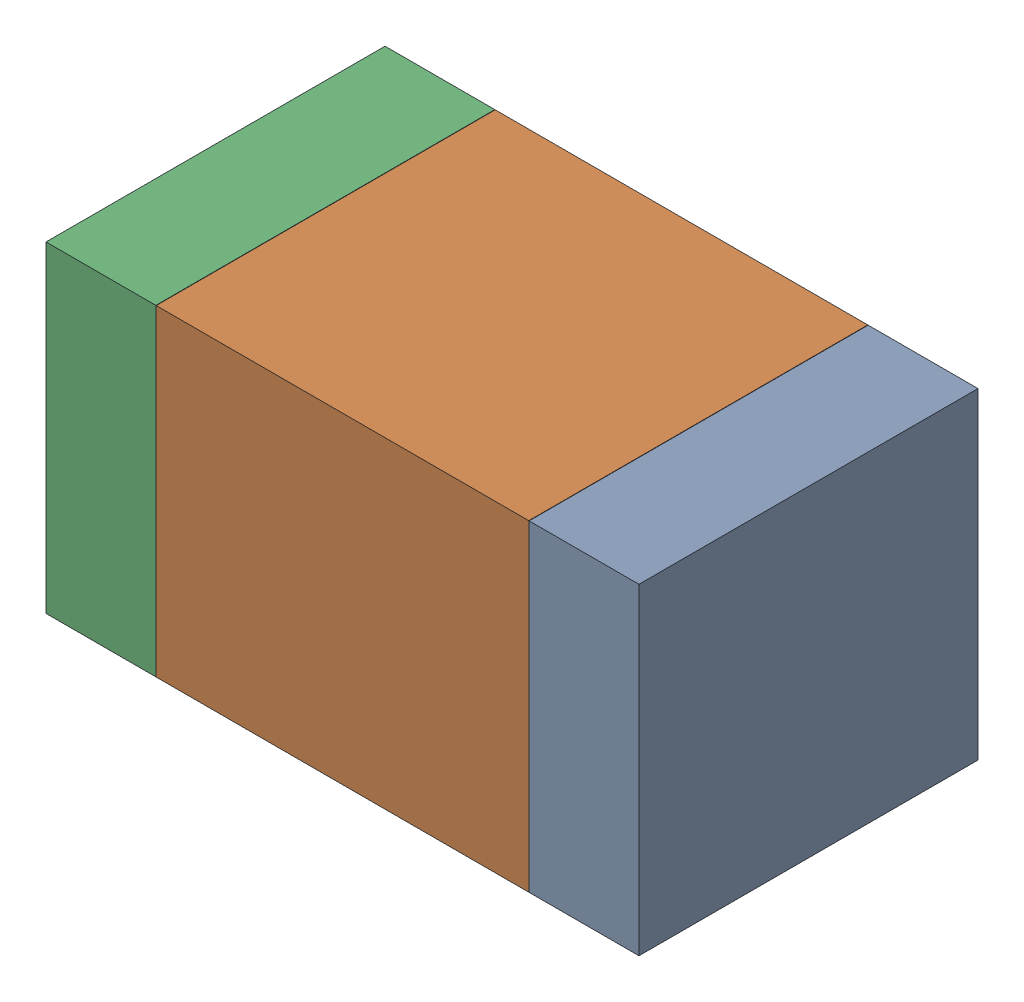
SolidWorks assembly R39, configuration Default. Lengths in mm.
Overall size (1.75 0.95 1).
6 component instances, 2 part files, 0 mates.
Components (placement in the parent):
- 6575498272-1: 6575498272 [Default] at (45.9245 13.589 0) size (0.32 0.95 1)
  - Extruded_8-1: Extruded_8 [Default] at origin size (0.32 0.95 1)
- 6575498112-1: 6575498112 [Default] at (45.212 13.589 0) size (1.1 0.95 1)
  - Extruded_9-1: Extruded_9 [Default] at origin size (1.1 0.95 1)
- 6575498272-2: 6575498272 [Default] at (44.4995 13.589 0) size (0.32 0.95 1)
  - Extruded_8-1: Extruded_8 [Default] at origin size (0.32 0.95 1)
